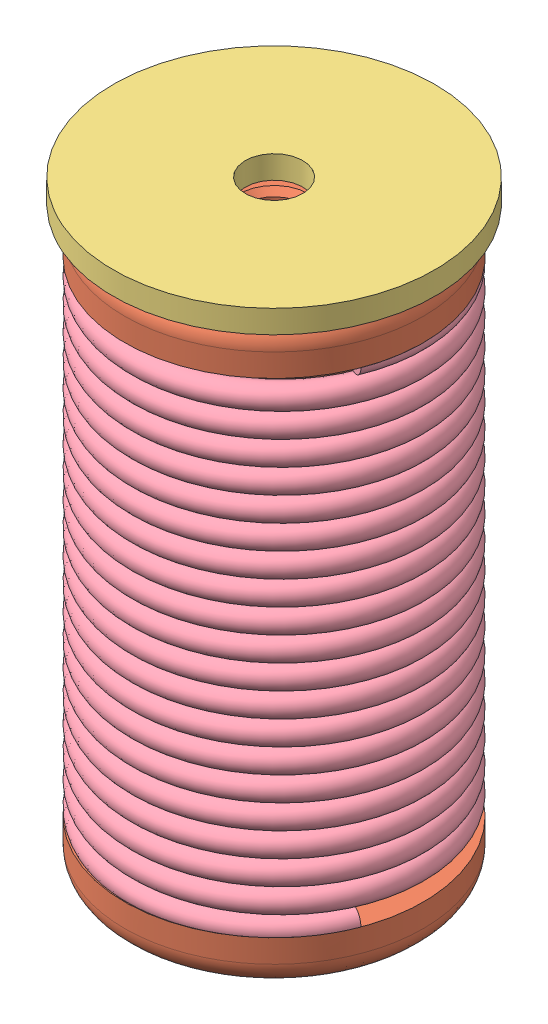
SolidWorks assembly mountainboardfinal-mpang, configuration Default. Lengths in mm.
Overall size (37.6 52.17 37.6).
5 component instances, 4 part files, 7 mates.
Components (placement in the parent):
- springdampener2-mpang-1: springdampener2-mpang [Default] at (4.7995 20.5182 34.4201) size (13.08 38 13.08)
- hw6springretainer-mpang-1: hw6springretainer-mpang [Default] at (4.7995 27.3895 34.4201) x (-0.710215 0 -0.703985) z (0.703985 0 -0.710215) size (26 17 26)
- fenderwasher2-mpang-1: fenderwasher2-mpang [Default] at (4.7995 46.3895 34.4201) x (-0.449349 0 0.893356) z (0 -1 0) size (28 28 2)
- hw6springretainer-mpang-2: hw6springretainer-mpang [Default] at (4.7995 11.2145 34.4201) x (-0.98623 0 -0.165378) z (-0.165378 0 0.98623) size (26 17 26)
- mountainbasespring-mpang-2: mountainbasespring-mpang [Default] at (16.0249 40.3895 38.6617) x (-0.935449 0 -0.353462) z (0 -1 0) size (28 29.44 44.17)
Mates (geometry in assembly coordinates):
- Coincident1: coincident aligned: plane of springdampener2-mpang-1 through (4.7995 38.3895 34.4201) normal (0 1 0); circle of hw6springretainer-mpang-1
- Concentric1: concentric aligned: circle of springdampener2-mpang-1; circle of hw6springretainer-mpang-1
- Coincident3: coincident anti-aligned: cone of springdampener2-mpang-1; cone of hw6springretainer-mpang-2 through (4.7995 -0.2855 34.4201) axis (0 -1 0)
- Coincident4: coincident anti-aligned: plane of hw6springretainer-mpang-1 through (4.7995 44.3895 34.4201) normal (0 1 0); plane of fenderwasher2-mpang-1 through (4.7995 44.3895 34.4201) normal (0 -1 0)
- Concentric2: concentric aligned: circle of hw6springretainer-mpang-1; circle of fenderwasher2-mpang-1
- Coincident9: coincident anti-aligned: plane of hw6springretainer-mpang-2 through (-4.9649 -1.7855 32.7828) normal (0 1 0); plane of mountainbasespring-mpang-2 through (16.0249 -1.7855 38.6617) normal (0 -1 0)
- Coincident10: coincident: point of fenderwasher2-mpang-1; line of mountainbasespring-mpang-2 through (4.7995 40.3895 34.4201) axis (0 -1 0)
